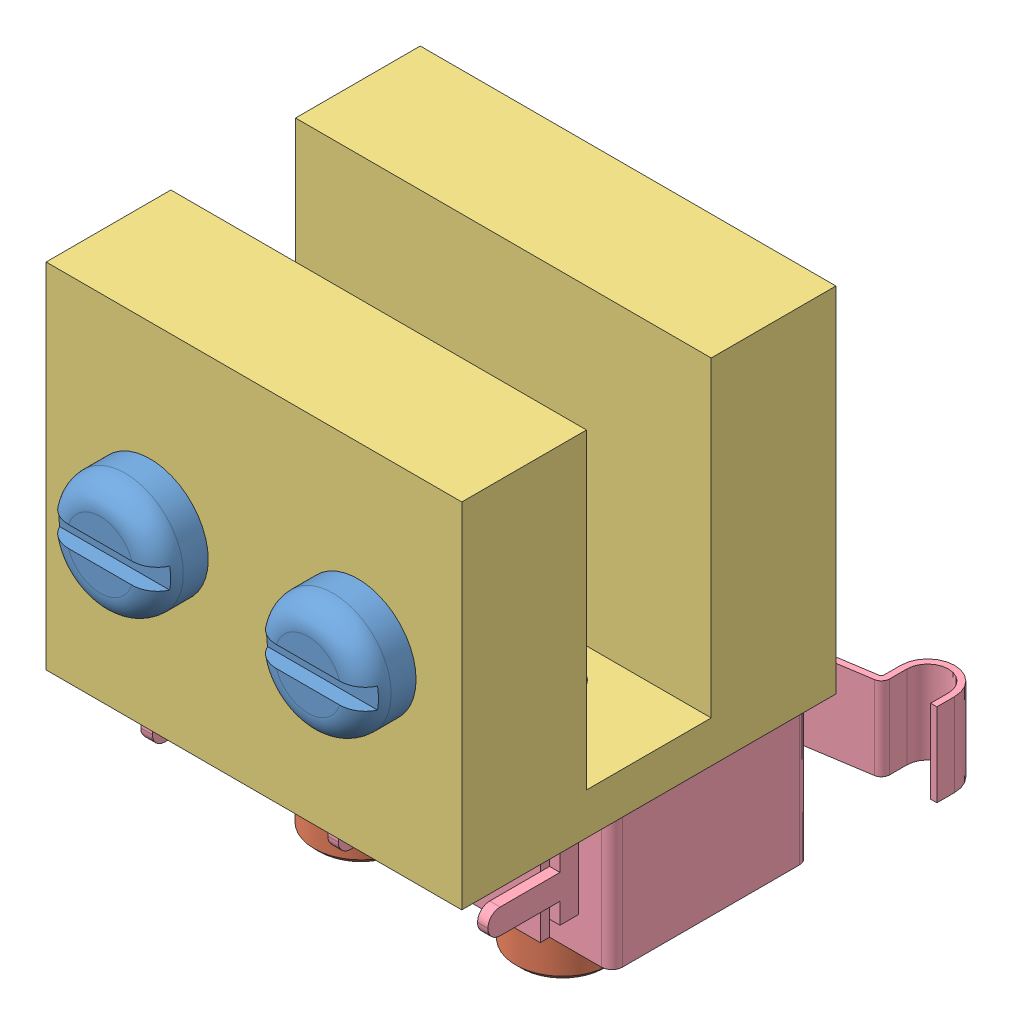
SolidWorks assembly y_endstop, configuration Défaut. Lengths in mm.
Overall size (21.67 26 25.83).
6 component instances, 4 part files, 14 mates.
Components (placement in the parent):
- pan slot head_am (threaded)-1: pan slot head_am (threaded) [B18.6.7M - M3 x 0.5 x 8 Slotted PHMS --8N] at (5 8.5 11.4) x (0 0 -1) z (-1 0 0) size (10.48 5.6 5.6)
- pan slot head_am (threaded)-2: pan slot head_am (threaded) [B18.6.7M - M3 x 0.5 x 8 Slotted PHMS --8N] at (-5 8.5 11.4) x (0 0 -1) z (-1 0 0) size (10.48 5.6 5.6)
- socket head cap screw_am-1: socket head cap screw_am [B18.3.1M - 2.5 x 0.45 x 8 Hex SHCS -- 8NHX] at (4.85 -9 -1) x (0 1 0) z (-0.866025 0 -0.5) size (10.5 4.5 4.5)
- socket head cap screw_am-2: socket head cap screw_am [B18.3.1M - 2.5 x 0.45 x 8 Hex SHCS -- 8NHX] at (-4.85 -9 -1) x (0 1 0) z (-0.866025 0 0.5) size (10.5 4.5 4.5)
- y_endstop_body-1: y_endstop_body [Défaut] at origin size (20 17 18)
- kw4A(S) microswitch-1: kw4A(S) microswitch [Default] at (0 -6.5 1.525) x (0 1 0) z (-1 0 0) size (6.5 20.24 21.62)
Mates (geometry in assembly coordinates):
- Coaxiale10: concentric aligned: cylinder of y_endstop_body-1 through (5 8.5 -9.001) axis (0 0 1) radius 1.5; cylinder of pan slot head_am (threaded)-1 through (5 8.5 36.8) axis (0 0 1) radius 2.8
- Coïncidente22: coincident anti-aligned: plane of y_endstop_body-1 through (0 17 9) normal (0 0 1); plane of pan slot head_am (threaded)-1 through (5 7 9) normal (0 0 -1)
- Coaxiale11: concentric aligned: cylinder of y_endstop_body-1 through (-5 8.5 -9.001) axis (0 0 1) radius 1.5; cylinder of pan slot head_am (threaded)-2 through (-5 8.5 36.8) axis (0 0 1) radius 2.8
- Coïncidente23: coincident anti-aligned: plane of y_endstop_body-1 through (0 17 9) normal (0 0 1); plane of pan slot head_am (threaded)-2 through (-5 7 9) normal (0 0 -1)
- Coïncidente40: coincident anti-aligned: plane of y_endstop_body-1 through (0 0 0) normal (0 -1 0); plane of kw4A(S) microswitch-1 through (9.25 0 -7.495) normal (0 1 0)
- Coaxiale96: concentric aligned: cylinder of kw4A(S) microswitch-1 through (4.85 0 -1) axis (0 -1 0) radius 1.275; cylinder of socket head cap screw_am-1 through (4.85 -40.75 -1) axis (0 -1 0) radius 2.25
- Coïncidente165: coincident anti-aligned: plane of kw4A(S) microswitch-1 through (9.25 -6.5 -7.495) normal (0 -1 0); plane of socket head cap screw_am-1 through (5.975 -6.5 -2.9486) normal (0 1 0)
- Coaxiale97: concentric aligned: cylinder of kw4A(S) microswitch-1 through (-4.85 0 -1) axis (0 -1 0) radius 1.275; cylinder of socket head cap screw_am-2 through (-4.85 -40.75 -1) axis (0 -1 0) radius 2.25
- Coïncidente166: coincident anti-aligned: plane of kw4A(S) microswitch-1 through (9.25 -6.5 -7.495) normal (0 -1 0); plane of socket head cap screw_am-2 through (-5.975 -6.5 -2.9486) normal (0 1 0)
- Coïncidente167: coordinate: point of y_endstop_body-1; point of assembly
- Coïncidente168: coincident aligned: plane of socket head cap screw_am-1 through (5.4403 -7.9 -2.0225) normal (0 0 1); plane of socket head cap screw_am-2 through (-5.4403 -7.9 -2.0225) normal (0 0 1)
- Coïncidente169: coincident aligned: line of pan slot head_am (threaded)-1 through (7.644 9 10.7) axis (-1 0 0); line of pan slot head_am (threaded)-2 through (-2.356 9 10.7) axis (-1 0 0)
- Coaxiale98: concentric aligned: cylinder of socket head cap screw_am-1 through (4.85 -40.75 -1) axis (0 -1 0) radius 1.25; cylinder of y_endstop_body-1 through (4.85 17.001 -1) axis (0 -1 0) radius 0.85
- Coaxiale99: concentric aligned: circle of socket head cap screw_am-2; circle of y_endstop_body-1
